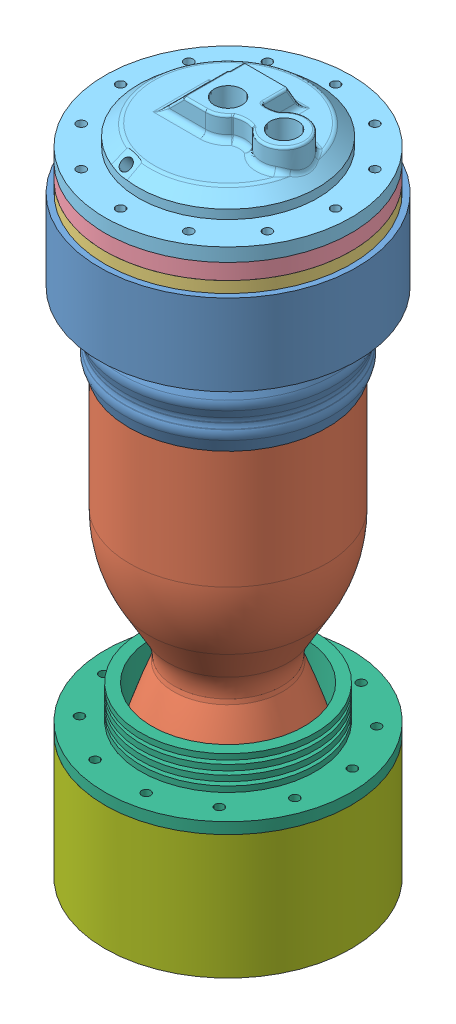
SolidWorks assembly Engine Assembly V5 BS2, configuration Default. Lengths in mm.
Overall size (197.22 383.41 197.22).
8 component instances, 7 part files, 7 mates.
Components (placement in the parent):
- FLANGE-1: FLANGE [Default] at origin size (146.05 87.13 146.05)
- Phenolic Thrust Chamber-1: Phenolic Thrust Chamber [Default] at (0 37.9853 0) x (0 -1 0) z (-0.664201 0 -0.747554) size (242.93 111.52 111.52)
- Injector Assembly V4-2-1: Injector Assembly V4-2 [Default] at (0 29.21 0) size (139.7 47.17 139.7)
  - Injector V4-1: Injector V4 [Default] x (1 0 0) z (0 0 -1) size (139.7 6.35 139.7)
  - Distribution Plate V4-1: Distribution Plate V4 [Default] at origin size (139.7 20.32 139.7)
  - Top Plate V4-1: Top Plate V4 [Default] at (0 8.89 0) size (139.7 31.93 139.7)
- V5 BS2 Extension Flange-1: V5 BS2 Extension Flange [Default] at (0 -242.9257 0) x (0.747554 0 -0.664201) z (-0.664201 0 -0.747554) size (139.7 25.4 139.7)
- Steel Nozzle Extension-2: Steel Nozzle Extension [Default] at (0 37.9853 0) x (0 -1 0) z (-0.664201 0 -0.747554) size (70.46 139.7 139.7)
Mates (geometry in assembly coordinates):
- Concentric1: concentric anti-aligned: cylinder of FLANGE-1 through (0 0 0) axis (0 -1 0) radius 55.7276; cylinder of Phenolic Thrust Chamber-1 through (0 37.9853 0) axis (0 1 0) radius 55.7587
- Coincident1: coincident anti-aligned: plane of FLANGE-1 through (-42.8625 0 0) normal (0 -1 0); plane of Phenolic Thrust Chamber-1 through (-41.6827 0 37.035) normal (0 1 0)
- Concentric2: concentric anti-aligned: cylinder of FLANGE-1 through (0 0 0) axis (0 -1 0) radius 73.025; cylinder of Injector Assembly V4-2-1/Injector V4-1 through (0 22.86 0) axis (0 1 0) radius 69.85
- Coincident2: coincident anti-aligned: plane of FLANGE-1 through (-73.025 22.86 0) normal (0 1 0); plane of Injector Assembly V4-2-1/Injector V4-1 through (0 22.86 0) normal (0 -1 0)
- Coincident20: coordinate: point of Phenolic Thrust Chamber-1; point of Steel Nozzle Extension-2
- Coincident23: coincident: point of Phenolic Thrust Chamber-1; point of V5 BS2 Extension Flange-1
- Concentric3: concentric anti-aligned: cylinder of V5 BS2 Extension Flange-1 through (-56.6453 -217.5257 -18.8203) axis (0 -1 0) radius 2.54; cylinder of Steel Nozzle Extension-2 through (-56.6453 -273.4057 -18.8203) axis (0 1 0) radius 2.54
